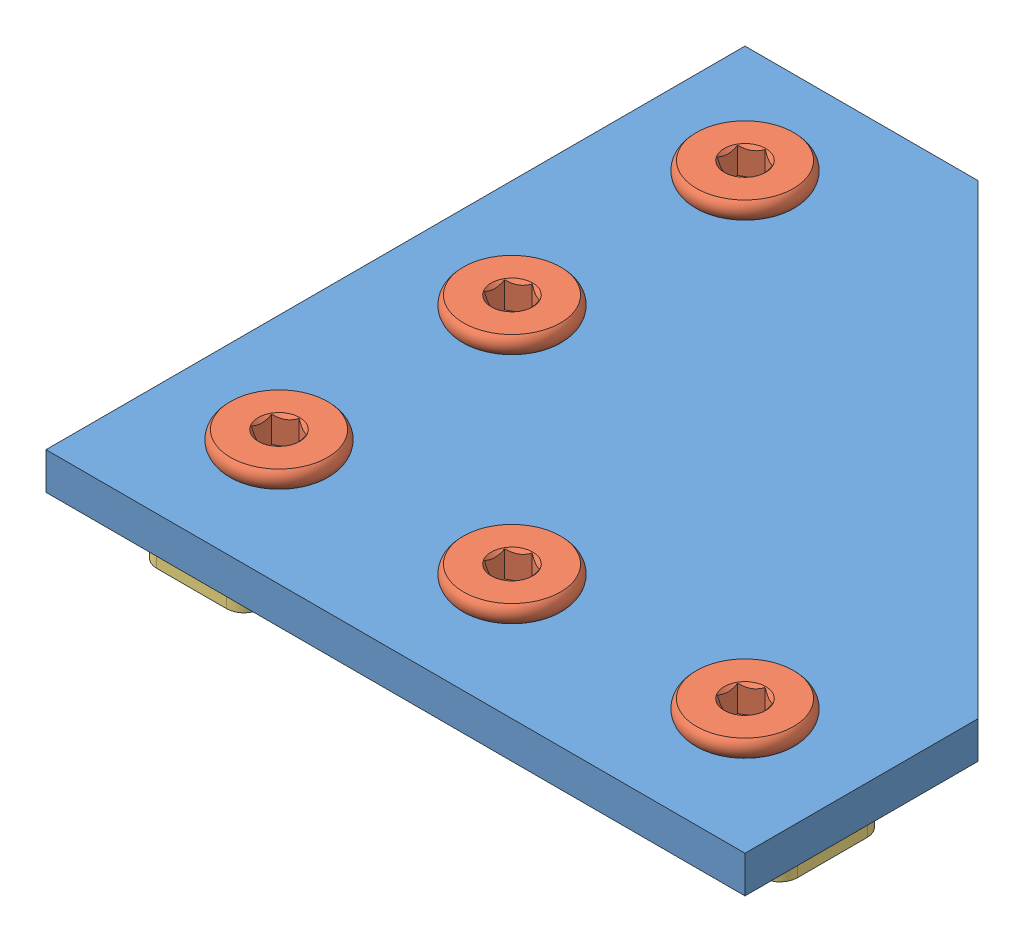
SolidWorks assembly Corner Bracket ASMB, configuration Corner D2. Lengths in mm.
Overall size (60 9.62 60).
11 component instances, 3 part files, 31 mates.
Components (placement in the parent):
- Corner Brackets-1: Corner Brackets [Default] at origin size (60 3.17 60)
- Low Profile Screw M5-1: Low Profile Screw M5 [M5 x 8] at (10 -4.825 -50) x (0 -1 0) z (-0.5 0 0.866025) size (9.62 9 9)
- Low Profile Screw M5-3: Low Profile Screw M5 [M5 x 8] at (10 -4.825 -30) x (0 -1 0) z (-0.5 0 0.866025) size (9.62 9 9)
- Low Profile Screw M5-4: Low Profile Screw M5 [M5 x 8] at (10 -4.825 -10) x (0 -1 0) z (-0.5 0 0.866025) size (9.62 9 9)
- Low Profile Screw M5-5: Low Profile Screw M5 [M5 x 8] at (30 -4.825 -10) x (0 -1 0) z (-0.5 0 0.866025) size (9.62 9 9)
- Low Profile Screw M5-6: Low Profile Screw M5 [M5 x 8] at (50 -4.825 -10) x (0 -1 0) z (-0.5 0 0.866025) size (9.62 9 9)
- Tee Nut-1: Tee Nut [Default] at (10 -1.8 -50) x (0 0 -1) z (0 -1 0) size (15 10 3)
- Tee Nut-2: Tee Nut [Default] at (10 -1.8 -30) x (0 0 1) z (0 -1 0) size (15 10 3)
- Tee Nut-3: Tee Nut [Default] at (10 -1.8 -10) x (0 0 1) z (0 -1 0) size (15 10 3)
- Tee Nut-4: Tee Nut [Default] at (30 -1.8 -10) x (1 0 0) z (0 -1 0) size (15 10 3)
- Tee Nut-5: Tee Nut [Default] at (50 -1.8 -10) x (1 0 0) z (0 -1 0) size (15 10 3)
Mates (geometry in assembly coordinates):
- Concentric1: concentric aligned: cylinder of Corner Brackets-1 through (10 3.175 -50) axis (0 -1 0) radius 2.6; cylinder of Low Profile Screw M5-1 through (10 3.175 -50) axis (0 -1 0) radius 2.5
- Coincident1: coincident anti-aligned: plane of Corner Brackets-1 through (0 3.175 0) normal (0 1 0); plane of Low Profile Screw M5-1 through (13.6039 3.175 -47.9193) normal (0 -1 0)
- Concentric2: concentric aligned: cylinder of Low Profile Screw M5-1 through (10 3.175 -50) axis (0 -1 0) radius 2.5; cylinder of Tee Nut-1 through (10 -4.8 -50) axis (0 -1 0) radius 2.1
- Distance1: distance = 1.8 mm anti-aligned: plane of Corner Brackets-1 through (0 0 0) normal (0 -1 0); plane of Tee Nut-1 through (13 -1.8 -56) normal (0 1 0)
- Parallel1: parallel aligned: plane of Corner Brackets-1 through (0 3.175 0) normal (-1 0 0); plane of Tee Nut-1 through (5 -3.4 -47) normal (-1 0 0)
- Concentric41: concentric aligned: cylinder of Corner Brackets-1 through (10 3.175 -30) axis (0 -1 0) radius 2.6; cylinder of Low Profile Screw M5-3 through (10 3.175 -30) axis (0 -1 0) radius 2.5
- Coincident51: coincident anti-aligned: plane of Corner Brackets-1 through (0 3.175 0) normal (0 1 0); plane of Low Profile Screw M5-3 through (13.6039 3.175 -27.9193) normal (0 -1 0)
- Concentric51: concentric aligned: cylinder of Corner Brackets-1 through (10 3.175 -10) axis (0 -1 0) radius 2.6; cylinder of Low Profile Screw M5-4 through (10 3.175 -10) axis (0 -1 0) radius 2.5
- Coincident61: coincident anti-aligned: plane of Corner Brackets-1 through (0 3.175 0) normal (0 1 0); plane of Low Profile Screw M5-4 through (13.6039 3.175 -7.9193) normal (0 -1 0)
- Concentric61: concentric aligned: cylinder of Corner Brackets-1 through (30 3.175 -10) axis (0 -1 0) radius 2.6; cylinder of Low Profile Screw M5-5 through (30 3.175 -10) axis (0 -1 0) radius 2.5
- Coincident71: coincident anti-aligned: plane of Corner Brackets-1 through (0 3.175 0) normal (0 1 0); plane of Low Profile Screw M5-5 through (33.6039 3.175 -7.9193) normal (0 -1 0)
- Concentric71: concentric aligned: cylinder of Corner Brackets-1 through (50 3.175 -10) axis (0 -1 0) radius 2.6; cylinder of Low Profile Screw M5-6 through (50 3.175 -10) axis (0 -1 0) radius 2.5
- Coincident81: coincident anti-aligned: plane of Corner Brackets-1 through (0 3.175 0) normal (0 1 0); plane of Low Profile Screw M5-6 through (53.6039 3.175 -7.9193) normal (0 -1 0)
- Concentric8: concentric aligned: cylinder of Low Profile Screw M5-3 through (10 3.175 -30) axis (0 -1 0) radius 2.5; cylinder of Tee Nut-2 through (10 -4.8 -30) axis (0 -1 0) radius 2.1
- Concentric9: concentric aligned: cylinder of Low Profile Screw M5-4 through (10 3.175 -10) axis (0 -1 0) radius 2.5; cylinder of Tee Nut-3 through (10 -4.8 -10) axis (0 -1 0) radius 2.1
- Concentric10: concentric aligned: cylinder of Low Profile Screw M5-5 through (30 3.175 -10) axis (0 -1 0) radius 2.5; cylinder of Tee Nut-4 through (30 -4.8 -10) axis (0 -1 0) radius 2.1
- Concentric11: concentric aligned: cylinder of Low Profile Screw M5-6 through (50 3.175 -10) axis (0 -1 0) radius 2.5; cylinder of Tee Nut-5 through (50 -4.8 -10) axis (0 -1 0) radius 2.1
- Coincident9: coincident aligned: plane of Tee Nut-1 through (13 -1.8 -56) normal (0 1 0); plane of Tee Nut-2 through (7 -1.8 -24) normal (0 1 0)
- Coincident10: coincident aligned: plane of Tee Nut-1 through (13 -1.8 -56) normal (0 1 0); plane of Tee Nut-3 through (7 -1.8 -4) normal (0 1 0)
- Coincident11: coincident aligned: plane of Tee Nut-1 through (13 -1.8 -56) normal (0 1 0); plane of Tee Nut-4 through (36 -1.8 -7) normal (0 1 0)
- Coincident12: coincident aligned: plane of Tee Nut-1 through (13 -1.8 -56) normal (0 1 0); plane of Tee Nut-5 through (56 -1.8 -7) normal (0 1 0)
- Parallel2: parallel aligned: plane of Corner Brackets-1 through (0 3.175 0) normal (-1 0 0); plane of Tee Nut-2 through (5 -3.4 -33) normal (-1 0 0)
- Parallel3: parallel aligned: plane of Tee Nut-3 through (5 -3.4 -13) normal (-1 0 0); plane of Corner Brackets-1 through (0 3.175 0) normal (-1 0 0)
- Parallel4: parallel aligned: plane of Corner Brackets-1 through (0 3.175 0) normal (0 0 1); plane of Tee Nut-4 through (27 -3.4 -5) normal (0 0 1)
- Parallel5: parallel aligned: plane of Corner Brackets-1 through (0 3.175 0) normal (0 0 1); plane of Tee Nut-5 through (47 -3.4 -5) normal (0 0 1)
- Parallel6: parallel aligned: plane of Corner Brackets-1 through (0 3.175 0) normal (-1 0 0); plane of Low Profile Screw M5-1 through (11.5 2.375 -49.134) normal (-1 0 0)
- Parallel7: parallel aligned: plane of Corner Brackets-1 through (0 3.175 0) normal (-1 0 0); plane of Low Profile Screw M5-3 through (11.5 2.375 -29.134) normal (-1 0 0)
- Parallel8: parallel aligned: plane of Corner Brackets-1 through (0 3.175 0) normal (-1 0 0); plane of Low Profile Screw M5-4 through (11.5 2.375 -9.134) normal (-1 0 0)
- Parallel9: parallel aligned: plane of Corner Brackets-1 through (0 3.175 0) normal (-1 0 0); plane of Low Profile Screw M5-5 through (31.5 2.375 -9.134) normal (-1 0 0)
- Parallel10: parallel aligned: plane of Corner Brackets-1 through (0 3.175 0) normal (-1 0 0); plane of Low Profile Screw M5-6 through (51.5 2.375 -9.134) normal (-1 0 0)
- Parallel11: parallel aligned: plane of Corner Brackets-1 through (0 3.175 0) normal (0 0 1); plane of Tee Nut-3 through (7 -3.4 -5) normal (0 0 1)
